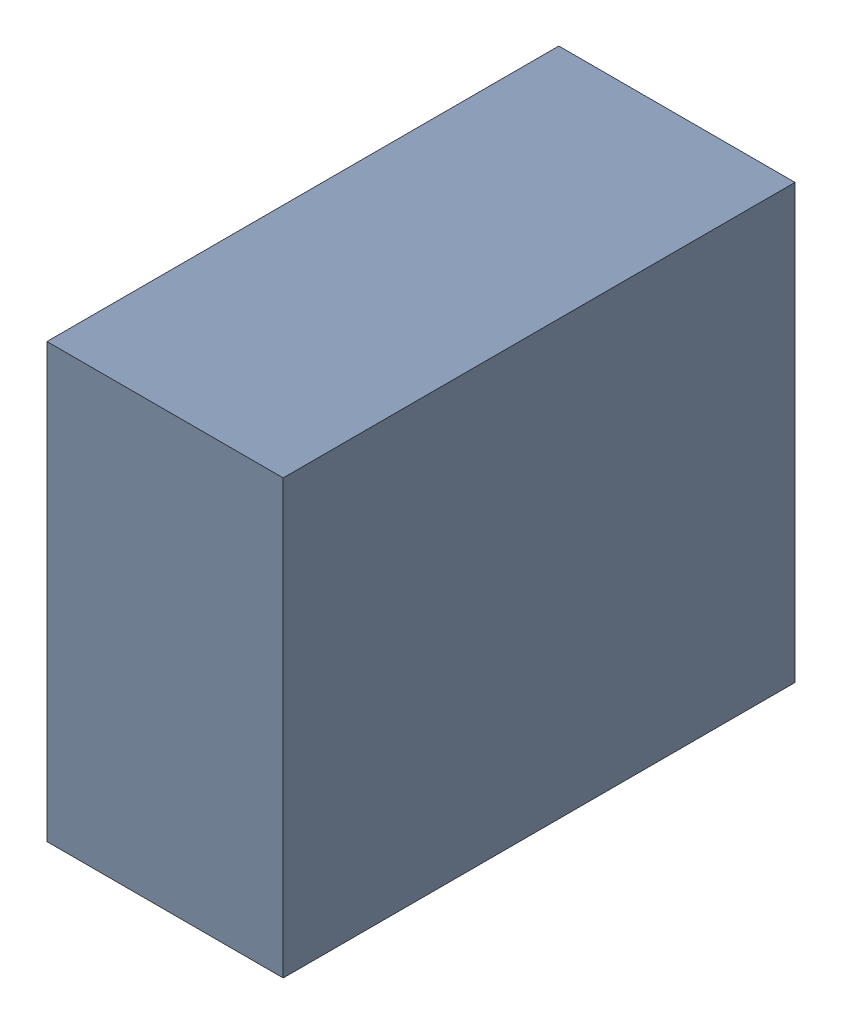
SolidWorks assembly C25_TDA1, configuration Standard. Lengths in mm.
Overall size (0.6 1.1 1.3).
2 component instances, 1 part files, 0 mates.
Components (placement in the parent):
- 885542376-1: 885542376 [Standard] at (1.98 42.04 0) size (0.6 1.1 1.3)
  - Extruded_25-1: Extruded_25 [Standard] at origin size (0.6 1.1 1.3)
